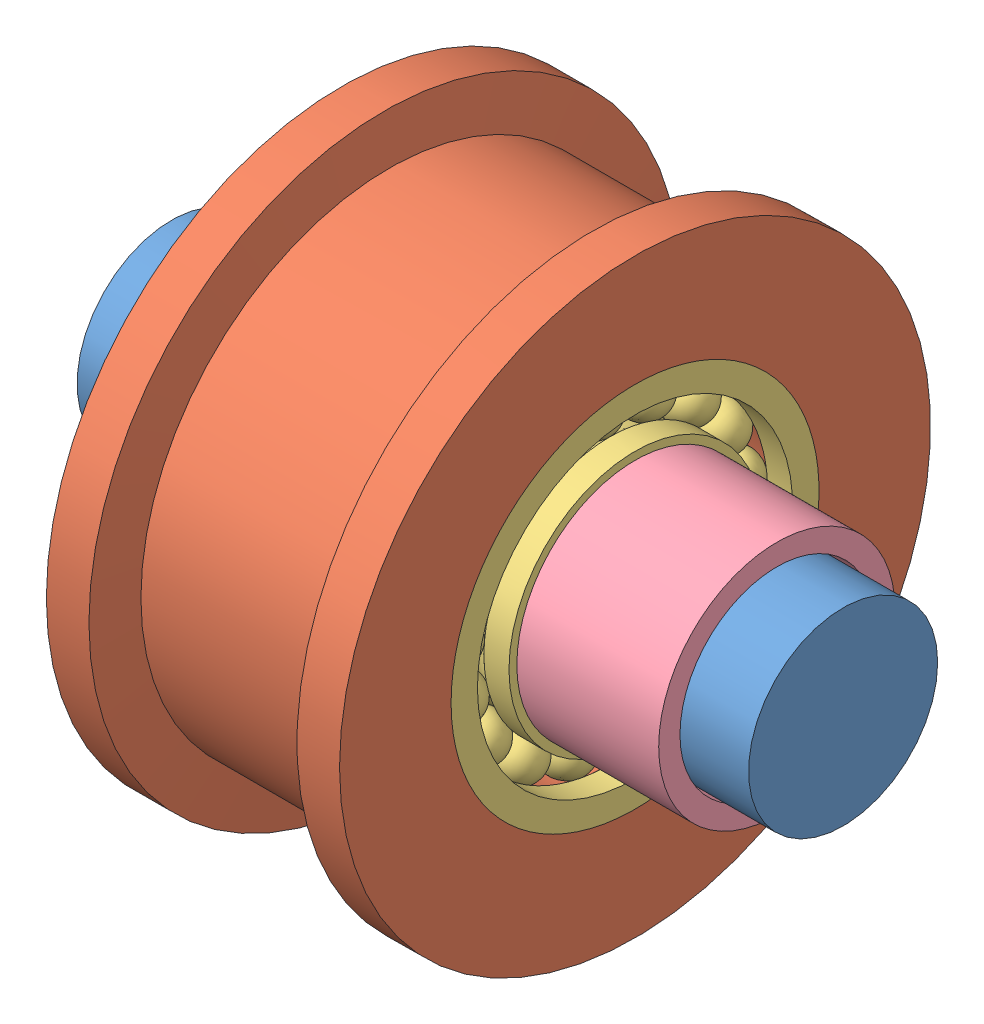
SolidWorks assembly 外臂托轮装配, configuration 默认. Lengths in mm.
Overall size (142 125 125).
6 component instances, 5 part files, 11 mates.
Components (placement in the parent):
- 外臂托轮轴-1: 外臂托轮轴 [默认] at (21.1631 -9.3836 -89.8065) x (0 0 -1) z (1 0 0) size (40 40 142)
- 外臂托轮-2: 外臂托轮 [默认] at (4118.0783 -9.3836 -7501.2898) size (62 125 125)
- deep groove ball bearings gb-3: deep groove ball bearings gb [Rolling bearings 6208 GB 276-94] at (-75.8369 -9.3836 -89.8065) size (18 80 80)
- deep groove ball bearings gb-4: deep groove ball bearings gb [Rolling bearings 6208 GB 276-94] at (-31.8369 -9.3836 -89.8065) size (18 80 80)
- 托轮轴套1-1: 托轮轴套1 [默认] at (-22.8369 0.6415 -19.916) x (0 0 -1) z (1 0 0) size (50 50 30)
- 托轮轴套2-1: 托轮轴套2 [默认] at (-84.8369 -33.984 -2.8589) x (0 0 1) z (-1 0 0) size (50 50 20)
Mates (geometry in assembly coordinates):
- 同心68: concentric: cylinder of 外臂托轮轴-1 through (-120.8369 -9.3836 -89.8065) axis (1 0 0) radius 20; cylinder of deep groove ball bearings gb-3 through (-82.8083 -9.3836 -89.8065) axis (-1 0 0) radius 20
- 同心69: concentric: cylinder of 外臂托轮轴-1 through (-120.8369 -9.3836 -89.8065) axis (1 0 0) radius 20; cylinder of deep groove ball bearings gb-4 through (-38.8083 -9.3836 -89.8065) axis (-1 0 0) radius 20
- 同心70: concentric: cylinder of 外臂托轮-2 through (-117.1001 -9.3836 -89.8065) axis (-1 0 0) radius 34; cylinder of deep groove ball bearings gb-4 through (-40.5476 -9.3836 -89.8065) axis (-1 0 0) radius 40
- 重合125: coincident: plane of 外臂托轮-2 through (-40.8369 -9.3836 -55.8065) normal (1 0 0); plane of deep groove ball bearings gb-4 through (-40.8369 30.6164 -89.8065) normal (-1 0 0)
- 重合126: coincident: plane of 外臂托轮-2 through (-66.8369 -9.3836 -58.8065) normal (-1 0 0); plane of deep groove ball bearings gb-3 through (-66.8369 30.6164 -89.8065) normal (1 0 0)
- 重合127: coincident: plane of 外臂托轮轴-1 through (21.1631 -9.3836 -89.8065) normal (1 0 0); plane of ? through (21.1631 -69.2671 -33.1168) normal (-1 0 0)
- 同心71: concentric: cylinder of 外臂托轮轴-1 through (-120.8369 -9.3836 -89.8065) axis (1 0 0) radius 20; cylinder of 托轮轴套2-1 through (-104.8369 -9.3836 -89.8065) axis (1 0 0) radius 20.5
- 重合128: coincident: plane of deep groove ball bearings gb-3 through (-84.8369 17.283 -89.8065) normal (-1 0 0); plane of 托轮轴套2-1 through (-84.8369 -9.3836 -89.8065) normal (1 0 0)
- 重合129: coincident: plane of deep groove ball bearings gb-4 through (-22.8369 30.6164 -89.8065) normal (1 0 0); plane of 托轮轴套1-1 through (-22.8369 -9.3836 -89.8065) normal (-1 0 0)
- 同心72: concentric: cylinder of 外臂托轮轴-1 through (-120.8369 -9.3836 -89.8065) axis (1 0 0) radius 20; cylinder of 托轮轴套1-1 through (7.1631 -9.3836 -89.8065) axis (-1 0 0) radius 20.5
- 距离1: distance = 14 mm: plane of 托轮轴套1-1 through (7.1631 -9.3836 -89.8065) normal (1 0 0); plane of ? through (21.1631 -69.2671 -33.1168) normal (-1 0 0)
